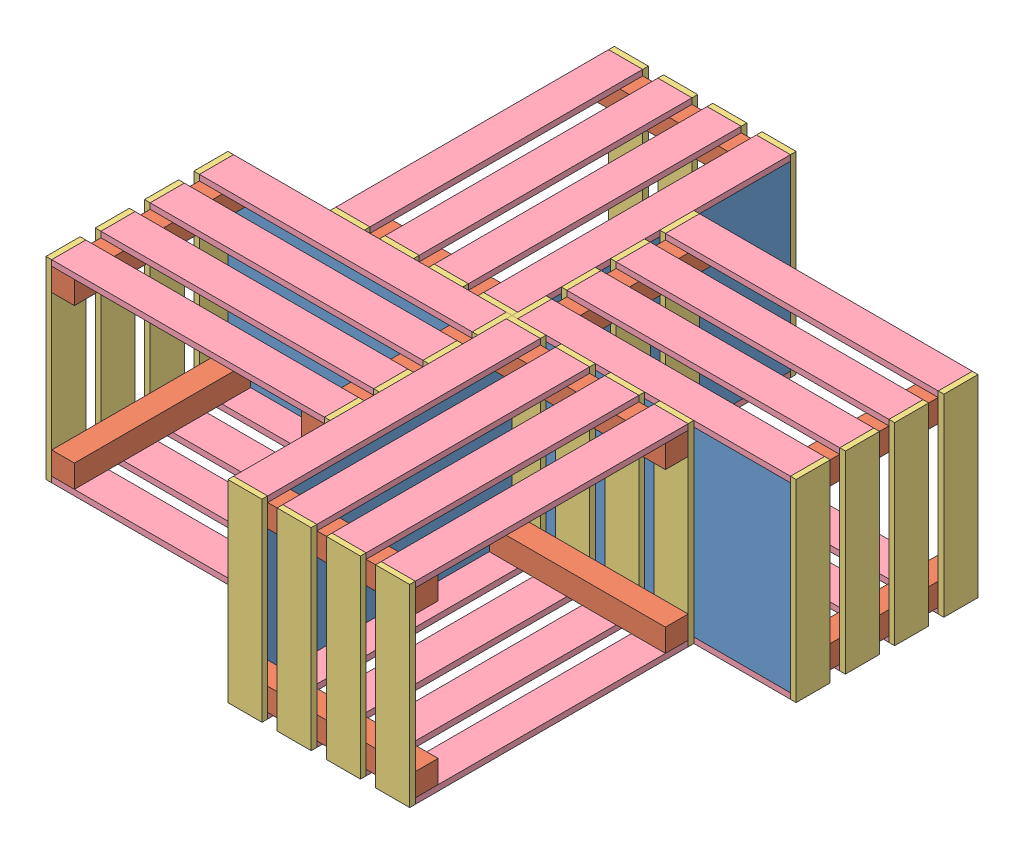
SolidWorks assembly pinwheel table, configuration Default. Lengths in mm.
Overall size (635 215.9 635).
92 component instances, 4 part files, 10 mates.
Components (placement in the parent):
- Assem2^pinwheel table-1: Assem2^pinwheel table [Default] at (59.6523 -77.584 111.1895) size (317.5 215.9 203.2) (virtual)
  - crate-1: crate [Default] at (-30.6466 -30.6112 -0.4738) size (317.5 215.9 203.2)
    - bottom-1: bottom [Default] at (-1.7472 114.5452 325.1624) size (304.8 203.2 6.35)
    - post-1: post [Default] at (-1.7472 114.5452 128.3124) size (25.4 25.4 196.85)
    - post-2: post [Default] at (-1.7472 292.3452 128.3124) size (25.4 25.4 196.85)
    - post-5: post [Default] at (277.6528 114.5452 128.3124) size (25.4 25.4 196.85)
    - post-7: post [Default] at (277.6528 292.3452 128.3124) size (25.4 25.4 196.85)
    - side width-1: side width [Default] at (-1.7472 324.0952 293.4124) x (0 -1 0) z (-1 0 0) size (215.9 38.1 6.35)
    - side width-2: side width [Default] at (-1.7472 108.1952 166.4124) x (0 1 0) z (-1 0 0) size (215.9 38.1 6.35)
    - side width-3: side width [Default] at (-1.7472 324.0952 183.3458) x (0 -1 0) z (-1 0 0) size (215.9 38.1 6.35)
    - side width-4: side width [Default] at (-1.7472 324.0952 238.3791) x (0 -1 0) z (-1 0 0) size (215.9 38.1 6.35)
    - side width-5: side width [Default] at (309.4028 324.0952 293.4124) x (0 -1 0) z (-1 0 0) size (215.9 38.1 6.35)
    - side width-6: side width [Default] at (309.4028 324.0952 238.3791) x (0 -1 0) z (-1 0 0) size (215.9 38.1 6.35)
    - side width-7: side width [Default] at (309.4028 324.0952 183.3458) x (0 -1 0) z (-1 0 0) size (215.9 38.1 6.35)
    - side width-8: side width [Default] at (309.4028 324.0952 128.3124) x (0 -1 0) z (-1 0 0) size (215.9 38.1 6.35)
    - side length-1: side length [Default] at (-1.7472 114.5452 293.4124) x (1 0 0) z (0 -1 0) size (304.8 38.1 6.35)
    - side length-2: side length [Default] at (-1.7472 114.5452 183.3458) x (1 0 0) z (0 -1 0) size (304.8 38.1 6.35)
    - side length-3: side length [Default] at (-1.7472 114.5452 238.3791) x (1 0 0) z (0 -1 0) size (304.8 38.1 6.35)
    - side length-4: side length [Default] at (-1.7472 114.5452 128.3124) x (1 0 0) z (0 -1 0) size (304.8 38.1 6.35)
    - side length-5: side length [Default] at (-1.7472 324.0952 293.4124) x (1 0 0) z (0 -1 0) size (304.8 38.1 6.35)
    - side length-6: side length [Default] at (-1.7472 324.0952 128.3124) x (1 0 0) z (0 -1 0) size (304.8 38.1 6.35)
    - side length-7: side length [Default] at (-1.7472 324.0952 183.3458) x (1 0 0) z (0 -1 0) size (304.8 38.1 6.35)
    - side length-8: side length [Default] at (-1.7472 324.0952 238.3791) x (1 0 0) z (0 -1 0) size (304.8 38.1 6.35)
- Assem2^pinwheel table-2: Assem2^pinwheel table [Default] at (-310.1301 -77.584 403.4843) x (0 0 -1) z (1 0 0) size (317.5 215.9 203.2) (virtual)
  - crate-1: crate [Default] at (-30.6466 -30.6112 -0.4738) size (317.5 215.9 203.2)
    - bottom-1: bottom [Default] at (-1.7472 114.5452 325.1624) size (304.8 203.2 6.35)
    - post-1: post [Default] at (-1.7472 114.5452 128.3124) size (25.4 25.4 196.85)
    - post-2: post [Default] at (-1.7472 292.3452 128.3124) size (25.4 25.4 196.85)
    - post-5: post [Default] at (277.6528 114.5452 128.3124) size (25.4 25.4 196.85)
    - post-7: post [Default] at (277.6528 292.3452 128.3124) size (25.4 25.4 196.85)
    - side width-1: side width [Default] at (-1.7472 324.0952 293.4124) x (0 -1 0) z (-1 0 0) size (215.9 38.1 6.35)
    - side width-2: side width [Default] at (-1.7472 108.1952 166.4124) x (0 1 0) z (-1 0 0) size (215.9 38.1 6.35)
    - side width-3: side width [Default] at (-1.7472 324.0952 183.3458) x (0 -1 0) z (-1 0 0) size (215.9 38.1 6.35)
    - side width-4: side width [Default] at (-1.7472 324.0952 238.3791) x (0 -1 0) z (-1 0 0) size (215.9 38.1 6.35)
    - side width-5: side width [Default] at (309.4028 324.0952 293.4124) x (0 -1 0) z (-1 0 0) size (215.9 38.1 6.35)
    - side width-6: side width [Default] at (309.4028 324.0952 238.3791) x (0 -1 0) z (-1 0 0) size (215.9 38.1 6.35)
    - side width-7: side width [Default] at (309.4028 324.0952 183.3458) x (0 -1 0) z (-1 0 0) size (215.9 38.1 6.35)
    - side width-8: side width [Default] at (309.4028 324.0952 128.3124) x (0 -1 0) z (-1 0 0) size (215.9 38.1 6.35)
    - side length-1: side length [Default] at (-1.7472 114.5452 293.4124) x (1 0 0) z (0 -1 0) size (304.8 38.1 6.35)
    - side length-2: side length [Default] at (-1.7472 114.5452 183.3458) x (1 0 0) z (0 -1 0) size (304.8 38.1 6.35)
    - side length-3: side length [Default] at (-1.7472 114.5452 238.3791) x (1 0 0) z (0 -1 0) size (304.8 38.1 6.35)
    - side length-4: side length [Default] at (-1.7472 114.5452 128.3124) x (1 0 0) z (0 -1 0) size (304.8 38.1 6.35)
    - side length-5: side length [Default] at (-1.7472 324.0952 293.4124) x (1 0 0) z (0 -1 0) size (304.8 38.1 6.35)
    - side length-6: side length [Default] at (-1.7472 324.0952 128.3124) x (1 0 0) z (0 -1 0) size (304.8 38.1 6.35)
    - side length-7: side length [Default] at (-1.7472 324.0952 183.3458) x (1 0 0) z (0 -1 0) size (304.8 38.1 6.35)
    - side length-8: side length [Default] at (-1.7472 324.0952 238.3791) x (1 0 0) z (0 -1 0) size (304.8 38.1 6.35)
- Assem2^pinwheel table-3: Assem2^pinwheel table [Default] at (-17.8353 -77.584 773.2667) x (-1 0 0) z (0 0 -1) size (317.5 215.9 203.2) (virtual)
  - crate-1: crate [Default] at (-30.6466 -30.6112 -0.4738) size (317.5 215.9 203.2)
    - bottom-1: bottom [Default] at (-1.7472 114.5452 325.1624) size (304.8 203.2 6.35)
    - post-1: post [Default] at (-1.7472 114.5452 128.3124) size (25.4 25.4 196.85)
    - post-2: post [Default] at (-1.7472 292.3452 128.3124) size (25.4 25.4 196.85)
    - post-5: post [Default] at (277.6528 114.5452 128.3124) size (25.4 25.4 196.85)
    - post-7: post [Default] at (277.6528 292.3452 128.3124) size (25.4 25.4 196.85)
    - side width-1: side width [Default] at (-1.7472 324.0952 293.4124) x (0 -1 0) z (-1 0 0) size (215.9 38.1 6.35)
    - side width-2: side width [Default] at (-1.7472 108.1952 166.4124) x (0 1 0) z (-1 0 0) size (215.9 38.1 6.35)
    - side width-3: side width [Default] at (-1.7472 324.0952 183.3458) x (0 -1 0) z (-1 0 0) size (215.9 38.1 6.35)
    - side width-4: side width [Default] at (-1.7472 324.0952 238.3791) x (0 -1 0) z (-1 0 0) size (215.9 38.1 6.35)
    - side width-5: side width [Default] at (309.4028 324.0952 293.4124) x (0 -1 0) z (-1 0 0) size (215.9 38.1 6.35)
    - side width-6: side width [Default] at (309.4028 324.0952 238.3791) x (0 -1 0) z (-1 0 0) size (215.9 38.1 6.35)
    - side width-7: side width [Default] at (309.4028 324.0952 183.3458) x (0 -1 0) z (-1 0 0) size (215.9 38.1 6.35)
    - side width-8: side width [Default] at (309.4028 324.0952 128.3124) x (0 -1 0) z (-1 0 0) size (215.9 38.1 6.35)
    - side length-1: side length [Default] at (-1.7472 114.5452 293.4124) x (1 0 0) z (0 -1 0) size (304.8 38.1 6.35)
    - side length-2: side length [Default] at (-1.7472 114.5452 183.3458) x (1 0 0) z (0 -1 0) size (304.8 38.1 6.35)
    - side length-3: side length [Default] at (-1.7472 114.5452 238.3791) x (1 0 0) z (0 -1 0) size (304.8 38.1 6.35)
    - side length-4: side length [Default] at (-1.7472 114.5452 128.3124) x (1 0 0) z (0 -1 0) size (304.8 38.1 6.35)
    - side length-5: side length [Default] at (-1.7472 324.0952 293.4124) x (1 0 0) z (0 -1 0) size (304.8 38.1 6.35)
    - side length-6: side length [Default] at (-1.7472 324.0952 128.3124) x (1 0 0) z (0 -1 0) size (304.8 38.1 6.35)
    - side length-7: side length [Default] at (-1.7472 324.0952 183.3458) x (1 0 0) z (0 -1 0) size (304.8 38.1 6.35)
    - side length-8: side length [Default] at (-1.7472 324.0952 238.3791) x (1 0 0) z (0 -1 0) size (304.8 38.1 6.35)
- Assem2^pinwheel table-4: Assem2^pinwheel table [Default] at (351.9471 -77.584 480.9719) x (0 0 1) z (-1 0 0) size (317.5 215.9 203.2) (virtual)
  - crate-1: crate [Default] at (-30.6466 -30.6112 -0.4738) size (317.5 215.9 203.2)
    - bottom-1: bottom [Default] at (-1.7472 114.5452 325.1624) size (304.8 203.2 6.35)
    - post-1: post [Default] at (-1.7472 114.5452 128.3124) size (25.4 25.4 196.85)
    - post-2: post [Default] at (-1.7472 292.3452 128.3124) size (25.4 25.4 196.85)
    - post-5: post [Default] at (277.6528 114.5452 128.3124) size (25.4 25.4 196.85)
    - post-7: post [Default] at (277.6528 292.3452 128.3124) size (25.4 25.4 196.85)
    - side width-1: side width [Default] at (-1.7472 324.0952 293.4124) x (0 -1 0) z (-1 0 0) size (215.9 38.1 6.35)
    - side width-2: side width [Default] at (-1.7472 108.1952 166.4124) x (0 1 0) z (-1 0 0) size (215.9 38.1 6.35)
    - side width-3: side width [Default] at (-1.7472 324.0952 183.3458) x (0 -1 0) z (-1 0 0) size (215.9 38.1 6.35)
    - side width-4: side width [Default] at (-1.7472 324.0952 238.3791) x (0 -1 0) z (-1 0 0) size (215.9 38.1 6.35)
    - side width-5: side width [Default] at (309.4028 324.0952 293.4124) x (0 -1 0) z (-1 0 0) size (215.9 38.1 6.35)
    - side width-6: side width [Default] at (309.4028 324.0952 238.3791) x (0 -1 0) z (-1 0 0) size (215.9 38.1 6.35)
    - side width-7: side width [Default] at (309.4028 324.0952 183.3458) x (0 -1 0) z (-1 0 0) size (215.9 38.1 6.35)
    - side width-8: side width [Default] at (309.4028 324.0952 128.3124) x (0 -1 0) z (-1 0 0) size (215.9 38.1 6.35)
    - side length-1: side length [Default] at (-1.7472 114.5452 293.4124) x (1 0 0) z (0 -1 0) size (304.8 38.1 6.35)
    - side length-2: side length [Default] at (-1.7472 114.5452 183.3458) x (1 0 0) z (0 -1 0) size (304.8 38.1 6.35)
    - side length-3: side length [Default] at (-1.7472 114.5452 238.3791) x (1 0 0) z (0 -1 0) size (304.8 38.1 6.35)
    - side length-4: side length [Default] at (-1.7472 114.5452 128.3124) x (1 0 0) z (0 -1 0) size (304.8 38.1 6.35)
    - side length-5: side length [Default] at (-1.7472 324.0952 293.4124) x (1 0 0) z (0 -1 0) size (304.8 38.1 6.35)
    - side length-6: side length [Default] at (-1.7472 324.0952 128.3124) x (1 0 0) z (0 -1 0) size (304.8 38.1 6.35)
    - side length-7: side length [Default] at (-1.7472 324.0952 183.3458) x (1 0 0) z (0 -1 0) size (304.8 38.1 6.35)
    - side length-8: side length [Default] at (-1.7472 324.0952 238.3791) x (1 0 0) z (0 -1 0) size (304.8 38.1 6.35)
Mates (geometry in assembly coordinates):
- Coincident2: coincident anti-aligned: plane of Assem2^pinwheel table-1/crate-1/side length-1 through (27.2585 0 404.1281) normal (0 -1 0); plane of assembly
- Coincident3: coincident aligned: plane of Assem2^pinwheel table-1/crate-1/side length-1 through (27.2585 0 404.1281) normal (0 -1 0); plane of Assem2^pinwheel table-4/crate-1/side length-1 through (59.0085 0 448.5781) normal (0 -1 0)
- Coincident7: coincident anti-aligned: plane of Assem2^pinwheel table-1/crate-1/bottom-1 through (27.2585 6.35 442.2281) normal (0 0 1); plane of Assem2^pinwheel table-4/crate-1/side width-1 through (59.0085 215.9 442.2281) normal (0 0 -1)
- Coincident8: coincident aligned: plane of Assem2^pinwheel table-1/crate-1/side width-1 through (20.9085 215.9 404.1281) normal (-1 0 0); plane of Assem2^pinwheel table-4/crate-1/bottom-1 through (20.9085 6.35 448.5781) normal (-1 0 0)
- Coincident9: coincident anti-aligned: plane of Assem2^pinwheel table-3/crate-1/side width-1 through (20.9085 215.9 480.3281) normal (1 0 0); plane of Assem2^pinwheel table-4/crate-1/bottom-1 through (20.9085 6.35 448.5781) normal (-1 0 0)
- Coincident10: coincident aligned: plane of Assem2^pinwheel table-1/crate-1/side length-1 through (27.2585 0 404.1281) normal (0 -1 0); plane of Assem2^pinwheel table-3/crate-1/side length-1 through (14.5585 0 480.3281) normal (0 -1 0)
- Coincident11: coincident anti-aligned: plane of Assem2^pinwheel table-1/crate-1/bottom-1 through (27.2585 6.35 442.2281) normal (0 0 1); plane of Assem2^pinwheel table-3/crate-1/bottom-1 through (14.5585 6.35 442.2281) normal (0 0 -1)
- Coincident12: coincident aligned: plane of Assem2^pinwheel table-1/crate-1/side length-1 through (27.2585 0 404.1281) normal (0 -1 0); plane of Assem2^pinwheel table-2/crate-1/side length-1 through (616.9864 0 435.8781) normal (0 -1 0)
- Coincident14: coincident anti-aligned: plane of Assem2^pinwheel table-2/crate-1/side width-1 through (-17.1915 215.9 442.2281) normal (0 0 1); plane of Assem2^pinwheel table-3/crate-1/bottom-1 through (14.5585 6.35 442.2281) normal (0 0 -1)
- Coincident15: coincident anti-aligned: plane of Assem2^pinwheel table-1/crate-1/side width-4 through (20.9085 215.9 349.0948) normal (-1 0 0); plane of Assem2^pinwheel table-2/crate-1/bottom-1 through (20.9085 6.35 435.8781) normal (1 0 0)
